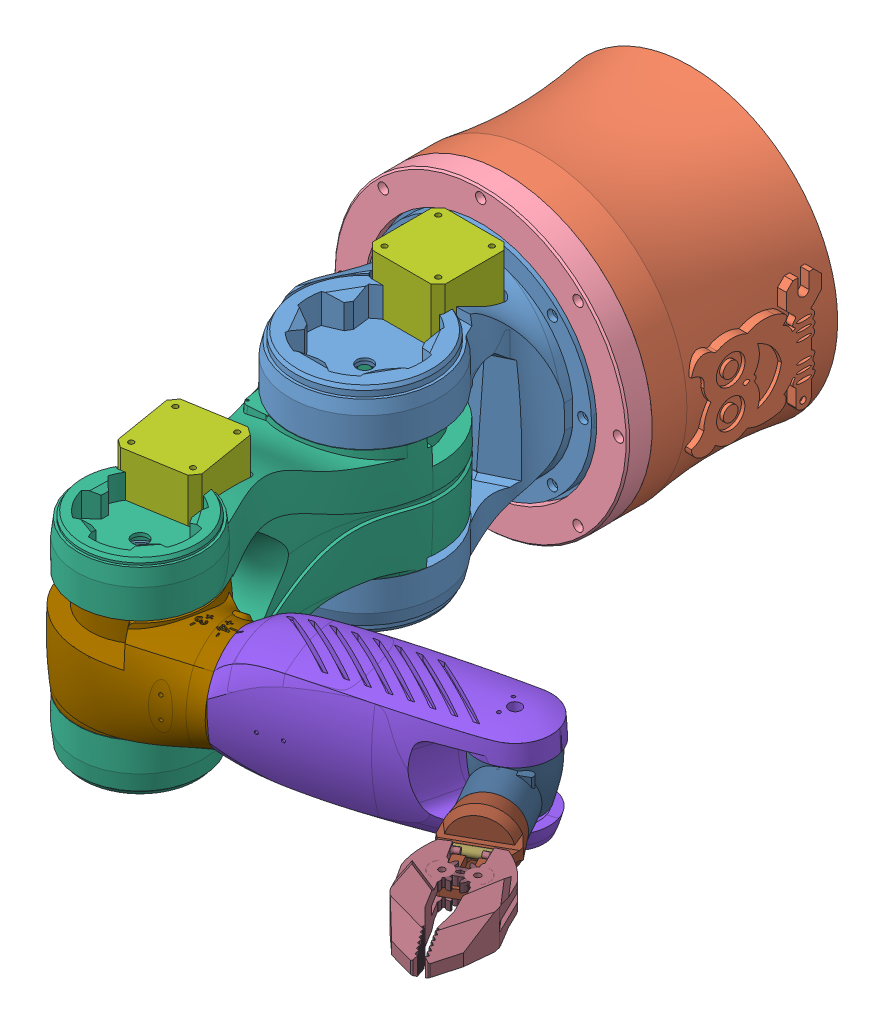
SolidWorks assembly Robot Arm New, configuration Domyślna. Lengths in mm.
Overall size (396.31 170 457.72).
57 component instances, 15 part files, 56 mates.
Components (placement in the parent):
- Base-1: Base [Domyślna] at (0 0 -274.858) size (145 145 134.73)
- Support-1: Support [Domyślna] at origin size (170 170 107)
- Ball-1: Ball [Default] at (-49.328 -3.3193 1.5741) x (0.766361 0.399042 0.503444) z (-0.305296 0.915757 -0.26112) size (8 8 8)
- Ring-1: Ring [Domyślna] at (3.9829 0 -274.858) x (0 0 -1) z (1 0 0) size (14.01 170 170)
- Nema 17 x 33-1: Nema 17 x 33 [Default] at (42.1555 0 -16.75) x (0 -1 0) z (0 0 -1) size (42 42 56.05) (hidden)
- Small Gear-1: Small Gear [Default] at (42.1555 0 0) x (0.815821 -0.578304 0) z (0 0 1) size (13.1 13.1 6.3)
- arm-1: arm [Całe ramię] at (-81.9619 3.8108 -365.0812) x (0.98649 0 -0.163824) z (0.163824 0 0.98649) size (92.9 119.57 238.58)
- Nema 17 x 33-2: Nema 17 x 33 [Default] at (10.2329 42 42.8) x (0 0 1) z (0 1 0) size (42 42 56.05)
- arm3-1: arm3 [Domyślna] at (-307.1433 0 -412.2215) x (0.955906 0 -0.293674) z (0.293674 0 0.955906) size (152.17 73.81 55.12)
- arm2-1: arm2 [Domyślna] at (-200.7096 1.3469 -431.8808) x (0.955906 0 -0.293674) z (0.293674 0 0.955906) size (97.18 73.94 92.73)
- arm5-1: arm5 [Domyślna] at (925.7767 0 665.3445) x (-0.87139 0 0.490592) z (-0.490592 0 -0.87139) size (40.21 35.25 58.35)
- Grasper Assembly-1: Grasper Assembly [Default] at (248.2606 0.9567 256.867) x (-0.87139 0 0.490592) z (-0.490592 0 -0.87139) size (51.49 36 114.44)
  - Grasper Body-1: Grasper Body [Default] at (0 0 18.5286) size (37.45 36 58.53)
  - Spring-1: Spring [Default] at (0 2.9735 -8.6) x (1 0 0) z (0 -0.96148 0.274876) size (18 5.2 5.2)
  - Grasper-8: Grasper [Domyślna] at (7.6 0 -30) x (0.060502 0 0.998168) z (0 1 0) size (80.6 25.49 20)
  - Grasper-9: Grasper [Domyślna] at (-7.6 0 -30) x (-0.060502 0 0.998168) z (0 -1 0) size (80.6 25.49 20)
- Nema 17 x 33-3: Nema 17 x 33 [Default] at (29.32 38.9282 208.4774) x (0.163824 0 0.98649) z (0 1 0) size (42 42 56.05)
- Small Gear-3: Small Gear [Default] at (29.32 22.1782 208.4774) x (0.815821 0 -0.578304) z (0 -1 0) size (13.1 13.1 6.3)
- Nema 17 x 33-4: Nema 17 x 33 [Default] at (42.1555 0 -15.45) x (0 -1 0) z (0 0 -1) size (42 42 56.05)
- Ball-2: Ball [Default] at (-47.4592 -13.6366 1.5741) x (0.673787 0.540885 0.503444) z (-0.478085 0.838601 -0.26112) size (8 8 8)
- Ball-3: Ball [Default] at (-43.6135 -23.391 1.5741) x (0.555319 0.661941 0.503444) z (-0.632501 0.729218 -0.26112) size (8 8 8)
- Ball-4: Ball [Default] at (-37.9387 -32.2078 1.5741) x (0.41551 0.757559 0.503444) z (-0.762611 0.591811 -0.26112) size (8 8 8)
- Ball-5: Ball [Default] at (-30.6528 -39.748 1.5741) x (0.259734 0.824065 0.503444) z (-0.863415 0.431661 -0.26112) size (8 8 8)
- Ball-6: Ball [Default] at (-22.036 -45.7219 1.5741) x (0.093976 0.858902 0.503444) z (-0.931037 0.254923 -0.26112) size (8 8 8)
- Ball-7: Ball [Default] at (-12.4192 -49.9 1.5741) x (-0.075393 0.860732 0.503444) z (-0.962881 0.068389 -0.26112) size (8 8 8)
- Ball-8: Ball [Default] at (-2.1722 -52.1217 1.5741) x (-0.241865 0.829485 0.503444) z (-0.957721 -0.120774 -0.26112) size (8 8 8)
- Ball-9: Ball [Default] at (8.3115 -52.3016 1.5741) x (-0.399042 0.766361 0.503444) z (-0.915757 -0.305296 -0.26112) size (8 8 8)
- Ball-10: Ball [Default] at (18.6287 -50.4328 1.5741) x (-0.540885 0.673787 0.503444) z (-0.838601 -0.478085 -0.26112) size (8 8 8)
- Ball-11: Ball [Default] at (28.3832 -46.5871 1.5741) x (-0.661941 0.555319 0.503444) z (-0.729218 -0.632501 -0.26112) size (8 8 8)
- Ball-12: Ball [Default] at (37.1999 -40.9123 1.5741) x (-0.757559 0.41551 0.503444) z (-0.591811 -0.762611 -0.26112) size (8 8 8)
- Ball-13: Ball [Default] at (44.7401 -33.6264 1.5741) x (-0.824065 0.259734 0.503444) z (-0.431661 -0.863415 -0.26112) size (8 8 8)
- Ball-14: Ball [Default] at (50.7141 -25.0096 1.5741) x (-0.858902 0.093976 0.503444) z (-0.254923 -0.931037 -0.26112) size (8 8 8)
- Ball-15: Ball [Default] at (54.8922 -15.3928 1.5741) x (-0.860732 -0.075393 0.503444) z (-0.068389 -0.962881 -0.26112) size (8 8 8)
- Ball-16: Ball [Default] at (57.1139 -5.1457 1.5741) x (-0.829485 -0.241865 0.503444) z (0.120774 -0.957721 -0.26112) size (8 8 8)
- Ball-17: Ball [Default] at (57.2937 5.3379 1.5741) x (-0.766361 -0.399042 0.503444) z (0.305296 -0.915757 -0.26112) size (8 8 8)
- Ball-18: Ball [Default] at (55.4249 15.6551 1.5741) x (-0.673787 -0.540885 0.503444) z (0.478085 -0.838601 -0.26112) size (8 8 8)
- Ball-19: Ball [Default] at (51.5792 25.4096 1.5741) x (-0.555319 -0.661941 0.503444) z (0.632501 -0.729218 -0.26112) size (8 8 8)
- Ball-20: Ball [Default] at (45.9044 34.2263 1.5741) x (-0.41551 -0.757559 0.503444) z (0.762611 -0.591811 -0.26112) size (8 8 8)
- Ball-21: Ball [Default] at (38.6186 41.7665 1.5741) x (-0.259734 -0.824065 0.503444) z (0.863415 -0.431661 -0.26112) size (8 8 8)
- Ball-22: Ball [Default] at (30.0017 47.7405 1.5741) x (-0.093976 -0.858902 0.503444) z (0.931037 -0.254923 -0.26112) size (8 8 8)
- Ball-23: Ball [Default] at (20.385 51.9186 1.5741) x (0.075393 -0.860732 0.503444) z (0.962881 -0.068389 -0.26112) size (8 8 8)
- Ball-24: Ball [Default] at (10.1379 54.1403 1.5741) x (0.241865 -0.829485 0.503444) z (0.957721 0.120774 -0.26112) size (8 8 8)
- Ball-25: Ball [Default] at (-0.3457 54.3202 1.5741) x (0.399042 -0.766361 0.503444) z (0.915757 0.305296 -0.26112) size (8 8 8)
- Ball-26: Ball [Default] at (-10.663 52.4513 1.5741) x (0.540885 -0.673787 0.503444) z (0.838601 0.478085 -0.26112) size (8 8 8)
- Ball-27: Ball [Default] at (-20.4174 48.6056 1.5741) x (0.661941 -0.555319 0.503444) z (0.729218 0.632501 -0.26112) size (8 8 8)
- Ball-28: Ball [Default] at (-29.2342 42.9308 1.5741) x (0.757559 -0.41551 0.503444) z (0.591811 0.762611 -0.26112) size (8 8 8)
- Ball-29: Ball [Default] at (-36.7744 35.645 1.5741) x (0.824065 -0.259734 0.503444) z (0.431661 0.863415 -0.26112) size (8 8 8)
- Ball-30: Ball [Default] at (-42.7484 27.0281 1.5741) x (0.858902 -0.093976 0.503444) z (0.254923 0.931037 -0.26112) size (8 8 8)
- Ball-31: Ball [Default] at (-46.9265 17.4114 1.5741) x (0.860732 0.075393 0.503444) z (0.068389 0.962881 -0.26112) size (8 8 8)
- Ball-32: Ball [Default] at (-49.1481 7.1643 1.5741) x (0.829485 0.241865 0.503444) z (-0.120774 0.957721 -0.26112) size (8 8 8)
- Bearing 608-1: Bearing 608 [Domyślna] at (16.4829 -33.2407 91.5) x (1 0 0) z (0 1 0) size (22 22 7)
- Bearing 608-2: Bearing 608 [Domyślna] at (16.4829 31.5 91.5) x (0.837169 0 0.546944) z (0 -1 0) size (22 22 7)
- Shaft 8x80-1: Shaft 8x80 [Domyślna] at (16.4829 1.2593 91.5) x (0.98903 0 0.147715) z (0 -1 0) size (8 8 80)
- Bearing 608-3: Bearing 608 [Domyślna] at (42.2852 -31.7407 246.8721) x (1 0 0.000468) z (0 1 0) size (22 22 7)
- Bearing 608-4: Bearing 608 [Domyślna] at (42.2852 35.0093 246.8721) x (0.425392 0 0.905009) z (0 -1 0) size (22 22 7)
- Shaft 8x80-2: Shaft 8x80 [Domyślna] at (42.2852 1.7593 246.8721) x (0.411131 0 -0.911576) z (0 1 0) size (8 8 80)
- Small Gear-4: Small Gear [Default] at (10.2329 25.25 42.8) x (0.815821 0 -0.578304) z (0 -1 0) size (13.1 13.1 6.3)
Mates (geometry in assembly coordinates):
- Wspólnie2: coincident anti-aligned: plane of Base-1 through (3.9829 1.0093 0) normal (0 0 -1); plane of assembly through (0 0 0) normal (0 0 1)
- Wspólnie3: coincident aligned: plane of Base-1 through (0 0 -274.858) normal (0 1 0); plane of assembly through (0 0 0) normal (0 1 0)
- Wspólnie4: coincident aligned: plane of Base-1 through (0 0 -274.858) normal (1 0 0); plane of assembly through (0 0 0) normal (1 0 0)
- Ustalone1: in place: plane of Support-1 through (0 0 0) normal (0 0 1); moOrthogonalPlaneRef_w of Support-1 through (0 0 0) normal (0 1 0); plane of Support-1 through (0 0 0) normal (1 0 0); unknown of Support-1
- Wspólnie5: coincident aligned: plane of Support-1; plane of assembly
- Wspólnie6: coincident aligned: plane of Support-1 through (0 0 0) normal (0 1 0); moOrthogonalPlaneRef_w of assembly
- Wspólnie7: coincident anti-aligned: plane of Support-1 through (0 0 0) normal (1 0 0); moOrthogonalPlaneRef_w of assembly
- Stycznie1: tangent: torus of Base-1; sphere of Ball-1
- Ustalone2: in place: plane of Base-1 through (3.9829 0 -274.858) normal (1 0 0); plane of Ring-1 through (3.9829 0 -274.858) normal (1 0 0); plane of Base-1 through (3.9829 0 -274.858) normal (1 0 0); line of Ring-1 through (0 -274.858 0) axis (1 0 0); plane of Base-1 through (3.9829 0 -274.858) normal (1 0 0); plane of Ring-1 through (3.9829 0 -274.858) normal (0 0 -1); plane of Base-1 through (3.9829 0 -274.858) normal (1 0 0); unknown of Ring-1
- Wspólnie8: coincident aligned: plane of Base-1; plane of Ring-1
- Wspólnie9: coincident aligned: moOrthogonalPlaneRef_w of Base-1 through (0 -274.858 0) axis (1 0 0); plane of Ring-1
- Wspólnie10: coincident anti-aligned: moOrthogonalPlaneRef_w of Base-1 through (0 -274.858 0) axis (0 1 0); plane of Ring-1 through (3.9829 0 -274.858) normal (0 0 -1)
- Koncentryczne1: concentric aligned: cylinder of Nema 17 x 33-1 through (42.1555 0 6.3) axis (0 0 -1) radius 2.5; cylinder of Small Gear-1 through (42.1555 0 6.3) axis (0 0 -1) radius 2.5
- Wspólnie11: coincident aligned: plane of Nema 17 x 33-1 through (42.1555 0 6.3) normal (0 0 1); plane of Small Gear-1 through (42.1555 0 6.3) normal (0 0 1)
- Wspólnie13: coincident aligned: plane of Base-1 through (3.9829 1.0093 0) normal (0 0 -1); plane of Small Gear-1 through (42.1555 0 0) normal (0 0 -1)
- Symetrycznie2: symmetric aligned: plane of Nema 17 x 33-1 through (63.1555 21 -49.75) normal (0 1 0); plane of Nema 17 x 33-1 through (63.1555 -21 -49.75) normal (0 -1 0); plane of assembly through (0 0 0) normal (0 1 0)
- Wspólnie20: coincident anti-aligned: plane of Base-1 through (16.4829 31.2593 91.5) normal (0 -1 0); plane of arm-1 through (16.4829 31.2593 91.5) normal (0 1 0)
- Koncentryczne4: concentric aligned: cylinder of Base-1 through (16.4829 -71.4907 91.5) axis (0 1 0) radius 4.5; cylinder of arm-1 through (16.4829 25.2593 91.5) axis (0 1 0) radius 34.25
- Wspólnie21: coincident anti-aligned: plane of Base-1 through (27.2329 42 25.3) normal (0 1 0); plane of Nema 17 x 33-2 through (10.2329 42 42.8) normal (0 -1 0)
- Wspólnie22: coincident anti-aligned: plane of Base-1 through (31.2329 42 59.8) normal (-1 0 0); plane of Nema 17 x 33-2 through (31.2329 75 21.8) normal (1 0 0)
- Wspólnie23: coincident anti-aligned: plane of Base-1 through (-7.2671 42 63.8) normal (0 0 -1); plane of Nema 17 x 33-2 through (-10.7671 75 63.8) normal (0 0 1)
- Wspólnie25: coincident anti-aligned: plane of arm3-1; plane of arm2-1
- Równolegle2: parallel aligned: plane of arm3-1; plane of arm2-1
- Koncentryczne9: concentric anti-aligned: cylinder of arm3-1 through (221.8773 1.7365 210.0049) axis (0 1 0) radius 14.5; cylinder of arm5-1 through (221.8773 -6.2933 210.0049) axis (0 -1 0) radius 14.5
- Wspólnie28: coincident aligned: plane of arm3-1; plane of arm5-1
- Równolegle3: parallel aligned: plane of ? through (7.9657 2.0185 -119) normal (0 0 -1); plane of arm5-1 through (354.231 0.8544 86.367) normal (0 0 -1)
- Koncentryczne12: concentric aligned: cylinder of arm5-1 through (240.5197 0.9567 243.1177) axis (0.490592 0 0.87139) radius 10; cylinder of Grasper Assembly-1/Grasper Body-1 through (236.7177 0.9567 236.3644) axis (0.490592 0 0.87139) radius 4
- Wspólnie34: coincident anti-aligned: plane of arm3-1; plane of arm2-1
- Koncentryczne13: concentric aligned: cylinder of arm-1 through (29.32 12.9282 208.4774) axis (0 1 0) radius 11.1; cylinder of Nema 17 x 33-3 through (29.32 15.8782 208.4774) axis (0 1 0) radius 2.5
- Koncentryczne14: concentric aligned: cylinder of arm-1 through (16.5687 40.2593 226.3072) axis (0 -1 0) radius 3; cylinder of Nema 17 x 33-3 through (16.5687 71.9282 226.3072) axis (0 -1 0) radius 1.5
- Wspólnie37: coincident aligned: plane of arm3-1; plane of assembly through (0 0 0) normal (0 1 0)
- Wspólnie38: coincident anti-aligned: plane of arm-1 through (49.1629 38.9282 222.6684) normal (0 1 0); plane of Nema 17 x 33-3 through (29.32 38.9282 208.4774) normal (0 -1 0)
- Koncentryczne18: concentric aligned: cylinder of Nema 17 x 33-3 through (29.32 15.8782 208.4774) axis (0 1 0) radius 2.5; cylinder of Small Gear-3 through (29.32 15.8782 208.4774) axis (0 1 0) radius 2.5
- Wspólnie41: coincident aligned: plane of Nema 17 x 33-3 through (29.32 15.8782 208.4774) normal (0 -1 0); plane of Small Gear-3 through (29.32 15.8782 208.4774) normal (0 -1 0)
- Wspólnie42: coincident anti-aligned: plane of Support-1 through (63.1555 17 42.0378) normal (-1 0 0); plane of Nema 17 x 33-4 through (63.1555 21 -48.45) normal (1 0 0)
- Koncentryczne19: concentric anti-aligned: cylinder of Support-1 through (26.6555 15.5 -2) axis (0 0 -1) radius 1.75; cylinder of Nema 17 x 33-4 through (26.6555 15.5 -48.45) axis (0 0 1) radius 1.5
- Wspólnie43: coincident anti-aligned: plane of Support-1 through (42.1555 0 -15.45) normal (0 0 -1); plane of Nema 17 x 33-4 through (42.1555 0 -15.45) normal (0 0 1)
- Koncentryczne20: concentric anti-aligned: cylinder of Base-1 through (16.4829 -38.7407 91.5) axis (0 1 0) radius 11.1; cylinder of Bearing 608-1 through (16.4829 -29.7407 91.5) axis (0 -1 0) radius 11
- Odległość4: distance = 2 mm anti-aligned: plane of Base-1 through (16.4829 -38.7407 91.5) normal (0 1 0); plane of Bearing 608-1 through (16.4829 -36.7407 91.5) normal (0 -1 0)
- Koncentryczne21: concentric aligned: cylinder of Base-1 through (16.4829 -38.7407 91.5) axis (0 1 0) radius 11.1; cylinder of Bearing 608-2 through (16.4829 28 91.5) axis (0 1 0) radius 11
- Odległość3: distance = 7 mm anti-aligned: plane of Base-1 through (16.4829 42 91.5) normal (0 -1 0); plane of Bearing 608-2 through (16.4829 35 91.5) normal (0 1 0)
- Koncentryczne22: concentric anti-aligned: cylinder of Bearing 608-1 through (16.4829 -29.7407 91.5) axis (0 -1 0) radius 4; cylinder of Shaft 8x80-1 through (16.4829 -38.7407 91.5) axis (0 1 0) radius 4
- Wspólnie47: coincident anti-aligned: plane of Base-1 through (16.4829 -38.7407 91.5) normal (0 1 0); plane of Shaft 8x80-1 through (16.4829 -38.7407 91.5) normal (0 -1 0)
- Koncentryczne23: concentric anti-aligned: cylinder of arm-1 through (42.2852 -49.1892 246.8721) axis (0 1 0) radius 11.1; cylinder of Bearing 608-3 through (42.2852 -28.2407 246.8721) axis (0 -1 0) radius 11
- Wspólnie48: coincident aligned: plane of arm-1 through (42.2852 -28.2407 246.8721) normal (0 1 0); plane of Bearing 608-3 through (42.2852 -28.2407 246.8721) normal (0 1 0)
- Koncentryczne24: concentric aligned: cylinder of arm-1 through (42.2852 -49.1892 246.8721) axis (0 1 0) radius 11.1; cylinder of Bearing 608-4 through (42.2852 31.5093 246.8721) axis (0 1 0) radius 11
- Wspólnie49: coincident aligned: plane of arm-1 through (42.2852 31.5093 246.8721) normal (0 -1 0); plane of Bearing 608-4 through (42.2852 31.5093 246.8721) normal (0 -1 0)
- Odległość5: distance = 3 mm aligned: plane of Shaft 8x80-2 through (42.2852 -38.2407 246.8721) normal (0 -1 0); plane of Bearing 608-3 through (42.2852 -35.2407 246.8721) normal (0 -1 0)
- Koncentryczne26: concentric aligned: cylinder of Nema 17 x 33-2 through (10.2329 18.95 42.8) axis (0 1 0) radius 2.5; cylinder of Small Gear-4 through (10.2329 18.95 42.8) axis (0 1 0) radius 2.5
- Wspólnie50: coincident aligned: plane of Nema 17 x 33-2 through (10.2329 18.95 42.8) normal (0 -1 0); plane of Small Gear-4 through (10.2329 18.95 42.8) normal (0 -1 0)
- Równolegle4: parallel anti-aligned: plane of Grasper Assembly-1/Grasper Body-1 through (239.1706 -1.5433 240.7214) normal (0 -1 0); plane of assembly through (0 0 0) normal (0 1 0)
- Koncentryczne27: concentric anti-aligned: cylinder of Bearing 608-4 through (42.2852 31.5093 246.8721) axis (0 1 0) radius 4; cylinder of Shaft 8x80-2 through (42.2852 41.7593 246.8721) axis (0 -1 0) radius 4
- Koncentryczne28: concentric aligned: cylinder of arm2-1 through (42.2852 38.7071 246.8721) axis (0 -1 0) radius 4.1; cylinder of Shaft 8x80-2 through (42.2852 41.7593 246.8721) axis (0 -1 0) radius 4
- Koncentryczne30: concentric aligned: cylinder of arm3-1 through (98.1506 1.7365 248.0163) axis (0.955906 0 -0.293674) radius 22.55; cylinder of arm2-1 through (93.7859 1.7365 249.3572) axis (0.955906 0 -0.293674) radius 22.5
- Wspólnie52: coincident anti-aligned: plane of arm3-1 through (98.5654 25.4865 247.8889) normal (-0.955906 0 0.293674); plane of arm2-1 through (105.5843 1.7365 270.735) normal (0.955906 0 -0.293674)
- Coincident1: coincident anti-aligned: plane of arm5-1 through (240.6424 0.9567 243.3355) normal (0.490592 0 0.87139); plane of Grasper Assembly-1/Grasper Body-1 through (240.6424 0.9567 243.3355) normal (-0.490592 0 -0.87139)
